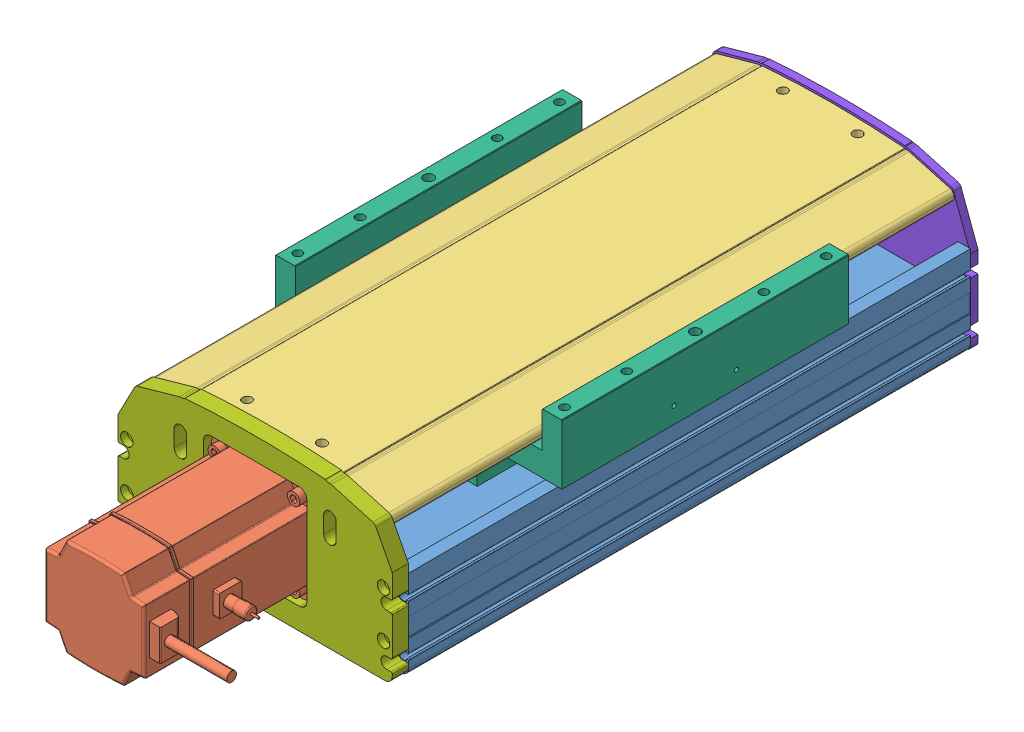
SolidWorks assembly S22-BC-750W, configuration 默认. Lengths in mm.
Overall size (238.5 122 599).
11 component instances, 9 part files, 34 mates.
Components (placement in the parent):
- S22-BC底座^S22-BC-750W-1: S22-BC底座^S22-BC-750W [默认] at origin size (220 72.2 451) (virtual)
- 750W电机^S22-BC-750W-1: 750W电机^S22-BC-750W [默认] at (0 60 367.5) x (0 -1 0) z (0 0 -1) size (82 139.7 182) (virtual)
- S22-BC上盖^S22-BC-750W-1: S22-BC上盖^S22-BC-750W [默认] at (0 117.9988 0) size (193.4 19.6 451) (virtual)
- EE-SX672 传感器^S22-BC-750W-1: EE-SX672 传感器^S22-BC-750W [默认] at (-116.75 60.1 -67.5) x (-1 0 0) z (0 0 1) size (13.5 27.4 26.1) (virtual)
- CFS22-GY外置感应片^S22-BC-750W-1: CFS22-GY外置感应片^S22-BC-750W [默认] at (-115.8 87 -7.7) x (0 0 -1) z (1 0 0) size (70 27 0.8) (virtual)
- EE-SX672 传感器^S22-BC-750W-2: EE-SX672 传感器^S22-BC-750W [默认] at (-116.75 60.1 -23.9) x (-1 0 0) z (0 0 1) size (13.5 27.4 26.1) (virtual)
- EE-SX672 传感器^S22-BC-750W-3: EE-SX672 传感器^S22-BC-750W [默认] at (-116.75 60.1 2.2) x (-1 0 0) z (0 0 1) size (13.5 27.4 26.1) (virtual)
- S22-BC-SFS25滑座^S22-BC-750W-1: S22-BC-SFS25滑座^S22-BC-750W [默认] at (0 0 -7.7) size (230 80 230) (virtual)
- 复件 电机板S22-BC-80^S22-BC-750W-1: 复件 电机板S22-BC-80^S22-BC-750W [Default] at (0 1.2 225.5) size (220 118 13) (virtual)
- 复件 端盖S22-T22M^S22-BC-750W-1: 复件 端盖S22-T22M^S22-BC-750W [默认] at (0 1.2 -231.5) size (220 118.5 6) (virtual)
- 复件 固定座架SF22-80-1^S22-BC-750W-1: 复件 固定座架SF22-80-1^S22-BC-750W [默认] at (13.0406 13.1744 120.5) size (164 84 15) (virtual)
Mates (geometry in assembly coordinates):
- 重合1: coincident: plane of S22-BC底座^S22-BC-750W-1 through (0 0 0) normal (1 0 0); plane of assembly through (0 0 0) normal (1 0 0)
- 重合2: coincident: plane of S22-BC底座^S22-BC-750W-1 through (0 0 0) normal (0 1 0); plane of assembly through (0 0 0) normal (0 1 0)
- 重合3: coincident: plane of S22-BC底座^S22-BC-750W-1 through (0 0 0) normal (0 0 1); plane of assembly through (0 0 0) normal (0 0 1)
- 平行1: parallel: plane of S22-BC底座^S22-BC-750W-1 through (110 16.25 225.5) normal (1 0 0); plane of 750W电机^S22-BC-750W-1 through (40 27 233.5) normal (1 0 0)
- 重合34: coincident: plane of S22-BC底座^S22-BC-750W-1 through (0 0 0) normal (0 0 1); plane of S22-BC上盖^S22-BC-750W-1 through (0 117.9988 0) normal (0 0 1)
- 重合36: coincident: plane of S22-BC底座^S22-BC-750W-1 through (0 0 0) normal (1 0 0); plane of S22-BC上盖^S22-BC-750W-1 through (0 117.9988 0) normal (1 0 0)
- 重合87: coincident: plane of S22-BC底座^S22-BC-750W-1 through (-110 16.25 225.5) normal (-1 0 0); plane of EE-SX672 传感器^S22-BC-750W-1 through (-110 71.2 -61.2) normal (1 0 0)
- 距离22: distance = 49 mm: plane of EE-SX672 传感器^S22-BC-750W-1 through (-110 49 -61.2) normal (0 -1 0); plane of S22-BC底座^S22-BC-750W-1 through (-110 0 225.5) normal (0 -1 0)
- 重合91: coincident: plane of EE-SX672 传感器^S22-BC-750W-2 through (-123.5 71.2 -17.6) normal (-1 0 0); plane of EE-SX672 传感器^S22-BC-750W-3 through (-123.5 71.2 8.5) normal (-1 0 0)
- 重合92: coincident: plane of EE-SX672 传感器^S22-BC-750W-1 through (-123.5 71.2 -61.2) normal (-1 0 0); plane of EE-SX672 传感器^S22-BC-750W-2 through (-123.5 71.2 -17.6) normal (-1 0 0)
- 重合93: coincident: plane of EE-SX672 传感器^S22-BC-750W-2 through (-110 49 -17.6) normal (0 -1 0); plane of EE-SX672 传感器^S22-BC-750W-3 through (-110 49 8.5) normal (0 -1 0)
- 重合94: coincident: plane of EE-SX672 传感器^S22-BC-750W-1 through (-110 49 -61.2) normal (0 -1 0); plane of EE-SX672 传感器^S22-BC-750W-2 through (-110 49 -17.6) normal (0 -1 0)
- 距离24: distance = 217 mm: plane of EE-SX672 传感器^S22-BC-750W-3 through (-123.5 49 8.5) normal (0 0 1); plane of S22-BC底座^S22-BC-750W-1 through (-104.5 14 225.5) normal (0 0 1)
- 重合96: coincident: plane of EE-SX672 传感器^S22-BC-750W-2 through (-113 52.2 -7.7) normal (0 0 1); plane of EE-SX672 传感器^S22-BC-750W-3 through (-113 52.2 -7.7) normal (0 0 -1)
- Distance1: distance = 122 mm: plane of S22-BC-SFS25滑座^S22-BC-750W-1 through (99 122 107.3) normal (0 1 0); plane of S22-BC底座^S22-BC-750W-1 through (110 0 225.5) normal (0 -1 0)
- Coincident2: coincident: plane of S22-BC底座^S22-BC-750W-1 through (0 0 0) normal (1 0 0); plane of S22-BC-SFS25滑座^S22-BC-750W-1 through (0 0 -7.7) normal (1 0 0)
- Distance3: distance = 117.9988 mm: plane of S22-BC上盖^S22-BC-750W-1 through (0 117.9988 0) normal (0 1 0); plane of S22-BC底座^S22-BC-750W-1 through (0 0 0) normal (0 1 0)
- Concentric1: concentric: cylinder of CFS22-GY外置感应片^S22-BC-750W-1 through (-115 87 17.3) axis (-1 0 0) radius 2.75; cylinder of S22-BC-SFS25滑座^S22-BC-750W-1 through (-115 87 17.3) axis (-1 0 0) radius 1.65
- Concentric2: concentric: cylinder of CFS22-GY外置感应片^S22-BC-750W-1 through (-115 87 -32.7) axis (-1 0 0) radius 2.75; cylinder of S22-BC-SFS25滑座^S22-BC-750W-1 through (-115 87 -32.7) axis (-1 0 0) radius 1.65
- Coincident3: coincident: plane of CFS22-GY外置感应片^S22-BC-750W-1 through (-115 91 26.3) normal (1 0 0); plane of S22-BC-SFS25滑座^S22-BC-750W-1 through (-115 122 107.3) normal (-1 0 0)
- 宽度1: width: plane of EE-SX672 传感器^S22-BC-750W-2 through (-123.5 49 -17.6) normal (0 0 1); plane of EE-SX672 传感器^S22-BC-750W-3 through (-123.5 49 2.2) normal (0 0 -1); plane of CFS22-GY外置感应片^S22-BC-750W-1 through (-115 65 -13.7) normal (0 0 -1); plane of CFS22-GY外置感应片^S22-BC-750W-1 through (-115 65 -1.7) normal (0 0 1)
- 重合97: coincident: plane of S22-BC底座^S22-BC-750W-1 through (-104.5 14 -225.5) normal (0 0 -1); plane of 复件 端盖S22-T22M^S22-BC-750W-1 through (92.7005 103.8004 -225.5) normal (0 0 1)
- 距离25: distance = 1.2 mm: plane of S22-BC底座^S22-BC-750W-1 through (-110 0 225.5) normal (0 -1 0); plane of 复件 端盖S22-T22M^S22-BC-750W-1 through (-110 1.2 -225.5) normal (0 -1 0)
- 宽度2: width: plane of 复件 端盖S22-T22M^S22-BC-750W-1 through (110 58.7 -225.5) normal (1 0 0); plane of 复件 端盖S22-T22M^S22-BC-750W-1 through (-110 18.7 -225.5) normal (-1 0 0); plane of S22-BC底座^S22-BC-750W-1 through (109.5 27.5 225.5) normal (1 0 0); plane of S22-BC底座^S22-BC-750W-1 through (-109.5 27.5 225.5) normal (-1 0 0)
- 重合99: coincident: plane of S22-BC底座^S22-BC-750W-1 through (-104.5 14 225.5) normal (0 0 1); plane of 复件 电机板S22-BC-80^S22-BC-750W-1 through (-59.6344 111.1404 225.5) normal (0 0 -1)
- 距离26: distance = 1.2 mm: plane of S22-BC底座^S22-BC-750W-1 through (110 0 225.5) normal (0 -1 0); plane of 复件 电机板S22-BC-80^S22-BC-750W-1 through (-104 1.2 238.5) normal (0 -1 0)
- 宽度3: width: plane of 复件 电机板S22-BC-80^S22-BC-750W-1 through (110 19.7 238.5) normal (1 0 0); plane of 复件 电机板S22-BC-80^S22-BC-750W-1 through (-110 19.7 238.5) normal (-1 0 0); plane of S22-BC底座^S22-BC-750W-1 through (-109.5 27.5 225.5) normal (-1 0 0); plane of S22-BC底座^S22-BC-750W-1 through (109.5 27.5 225.5) normal (1 0 0)
- 距离27: distance = 0 mm: plane of 750W电机^S22-BC-750W-1 through (0 60 225.5) normal (0 0 -1); plane of 复件 电机板S22-BC-80^S22-BC-750W-1 through (-59.6344 111.1404 225.5) normal (0 0 -1)
- 距离28: distance = 164 mm: plane of EE-SX672 传感器^S22-BC-750W-1 through (-123.5 49 -67.5) normal (0 0 -1); plane of 复件 端盖S22-T22M^S22-BC-750W-1 through (92.7005 103.8004 -231.5) normal (0 0 -1)
- 距离29: distance = 70 mm: plane of 750W电机^S22-BC-750W-1 through (-40 100 367.5) normal (-1 0 0); plane of 复件 电机板S22-BC-80^S22-BC-750W-1 through (-110 60.7 238.5) normal (-1 0 0)
- 距离34: distance = 20 mm: plane of 750W电机^S22-BC-750W-1 through (-33 20 233.5) normal (0 -1 0); plane of S22-BC底座^S22-BC-750W-1 through (110 0 225.5) normal (0 -1 0)
- 同心1: concentric: cylinder of 750W电机^S22-BC-750W-1 through (0 60 222.5) axis (0 0 -1) radius 9.5; cylinder of 复件 固定座架SF22-80-1^S22-BC-750W-1 through (0 60 225.5) axis (0 0 1) radius 30
- 重合100: coincident: plane of 750W电机^S22-BC-750W-1 through (0 60 225.5) normal (0 0 -1); plane of 复件 固定座架SF22-80-1^S22-BC-750W-1 through (-50 35 225.5) normal (0 0 1)
- 相切2: tangent: cylinder of 750W电机^S22-BC-750W-1 through (0 -170 367.5) axis (0 0 -1) radius 270; plane of 复件 固定座架SF22-80-1^S22-BC-750W-1 through (16.5 100 225.5) normal (0 1 0)
